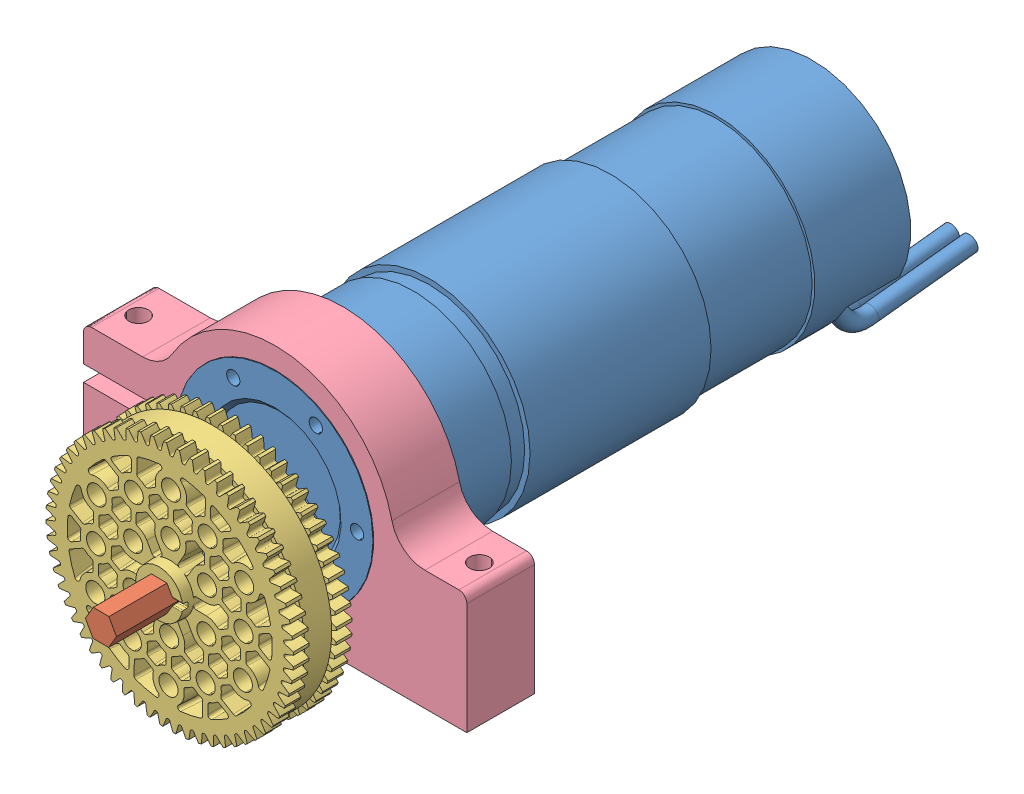
SolidWorks assembly Assem6, configuration Default. Lengths in mm.
Overall size (72 53.32 154.16).
5 component instances, 4 part files, 4 mates.
Components (placement in the parent):
- PART_ASSEM_MotorHDHexRotating-1: PART_ASSEM_MotorHDHexRotating [Default] at (123.9138 193.7516 -3.1381) x (-1 0 0) z (0 0 1) size (38 39.44 154.16)
  - PART_MotorHDHex_Shell-1: PART_MotorHDHex_Shell [Default] at (52.6409 85.4657 114.2715) size (38 39.44 128.25)
  - PART_MotorHDHex_RotatingHex-1: PART_MotorHDHex_RotatingHex [Default] at (52.6787 94.995 172.8795) x (0.858442 -0.512911 0) z (0.512911 0.858442 0) size (5.06 33.53 5.84)
- PART_Gear60Tooth-1: PART_Gear60Tooth [Default] at (71.2905 101.3153 151.3334) x (-0.014973 -0.999888 0) z (0 0 1) size (47.04 47.04 15)
- PART_MotorMount-1: PART_MotorMount [Default] at (60.1323 108.1718 136.6122) size (72 44.98 12.7)
Mates (geometry in assembly coordinates):
- Concentric1: concentric aligned: circle of PART_ASSEM_MotorHDHexRotating-1/PART_MotorHDHex_Shell-1; circle of PART_MotorMount-1
- Coincident2: coincident: plane of PART_ASSEM_MotorHDHexRotating-1/PART_MotorHDHex_RotatingHex-1 through (69.8505 103.8372 136.2134) normal (0.014973 0.999888 0); plane of PART_Gear60Tooth-1 through (69.8847 103.8367 151.3334) normal (-0.014973 -0.999888 0)
- Coincident3: coincident: plane of PART_ASSEM_MotorHDHexRotating-1/PART_MotorHDHex_RotatingHex-1 through (72.7711 103.7934 136.2134) normal (0.873415 0.486977 0); plane of PART_Gear60Tooth-1 through (72.7711 103.7934 151.3334) normal (-0.873415 -0.486977 0)
- Coincident4: coincident anti-aligned: plane of PART_ASSEM_MotorHDHexRotating-1/PART_MotorHDHex_Shell-1 through (71.2729 101.2859 143.8334) normal (0 0 1); plane of PART_Gear60Tooth-1 through (71.2905 101.3153 143.8334) normal (0 0 -1)
